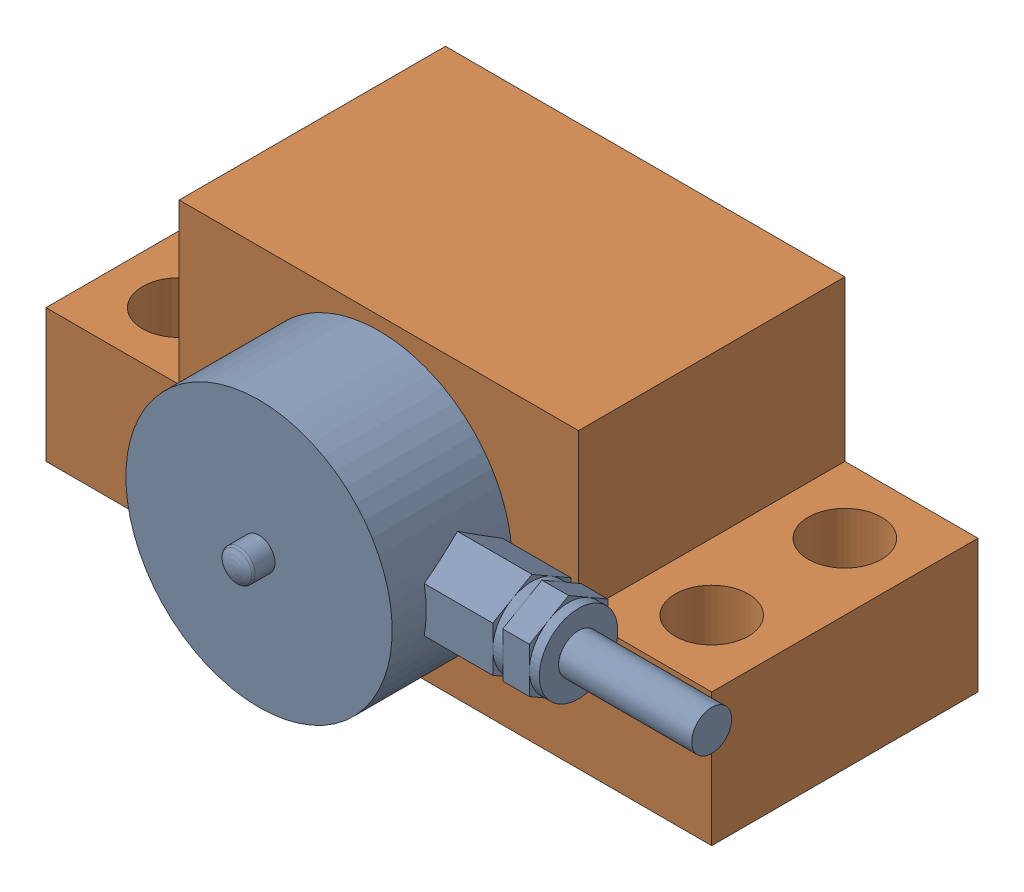
SolidWorks assembly loadcel yatay montaj-3, configuration Default. Lengths in mm.
Overall size (53.5 22 31).
2 component instances, 2 part files, 0 mates.
Components (placement in the parent):
- Mini_Loadcell-1: Mini_Loadcell [Default] at (0 11 19) x (-1 0 0) z (0 1 0) size (38.5 12 20)
- Loadcell yatay ayak-1: Loadcell yatay ayak [Default] at origin size (50 22 20)
